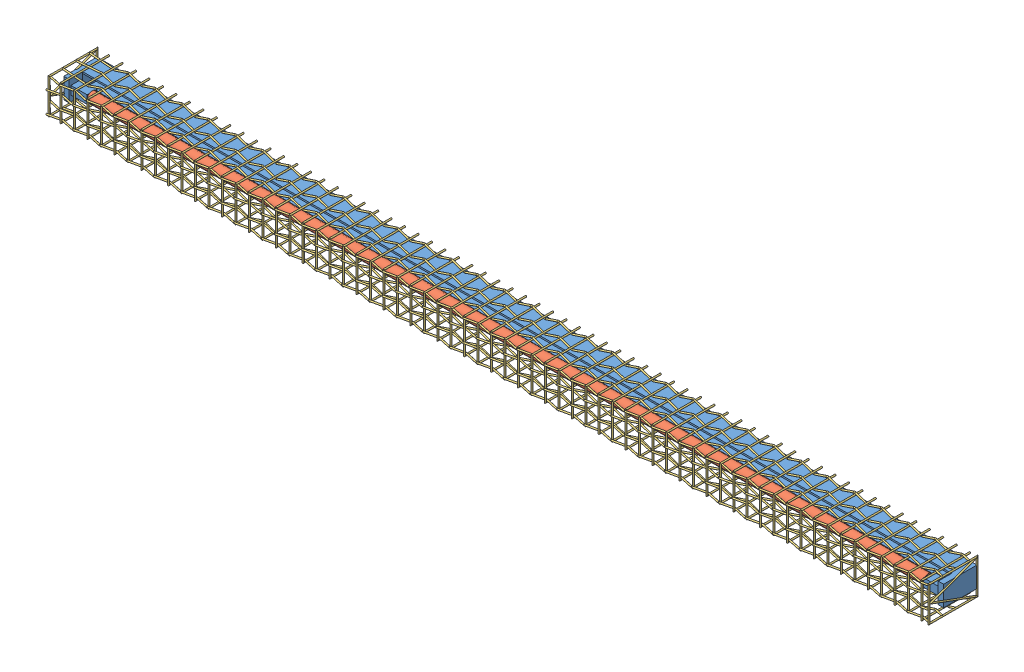
SolidWorks assembly UVC Light Assembly, configuration Default. Lengths in mm.
Overall size (1639.04 74.06 94.28).
3 component instances, 3 part files, 5 mates.
Components (placement in the parent):
- UVC Mounting-1: UVC Mounting [Default] at origin size (1635 38 62)
- GPHHA1554T6L-1: GPHHA1554T6L [Default] at (40.226 18.996 49.504) x (1 0 0) z (0 -0.93755 0.347851) size (1574 19 19)
- UVC Wire Guard-1: UVC Wire Guard [Default] at (1622 -9.3927 89) x (0 -1 0) z (1 0 0) size (74.06 94.28 1639.04)
Mates (geometry in assembly coordinates):
- Coincident1: coincident anti-aligned: circle of UVC Mounting-1; circle of GPHHA1554T6L-1
- Coincident2: coincident anti-aligned: plane of Mesh-1 through (1622 -9.3927 0) normal (0 0 -1)
- Concentric1: concentric anti-aligned: line of UVC Mounting-1 through (38 1635 0) axis (0 0 1); cylinder of Mesh-1 through (1635 53.6489 0) axis (0 -1 0) radius 1.32
- Parallel2: parallel aligned: plane of UVC Mounting-1 through (0 0 0) normal (0 0 -1); plane of Mesh-1 through (22 51.4673 0) normal (0 0 -1)
- Lock1: lock: unknown of UVC Mounting-1; unknown of UVC Wire Guard-1
